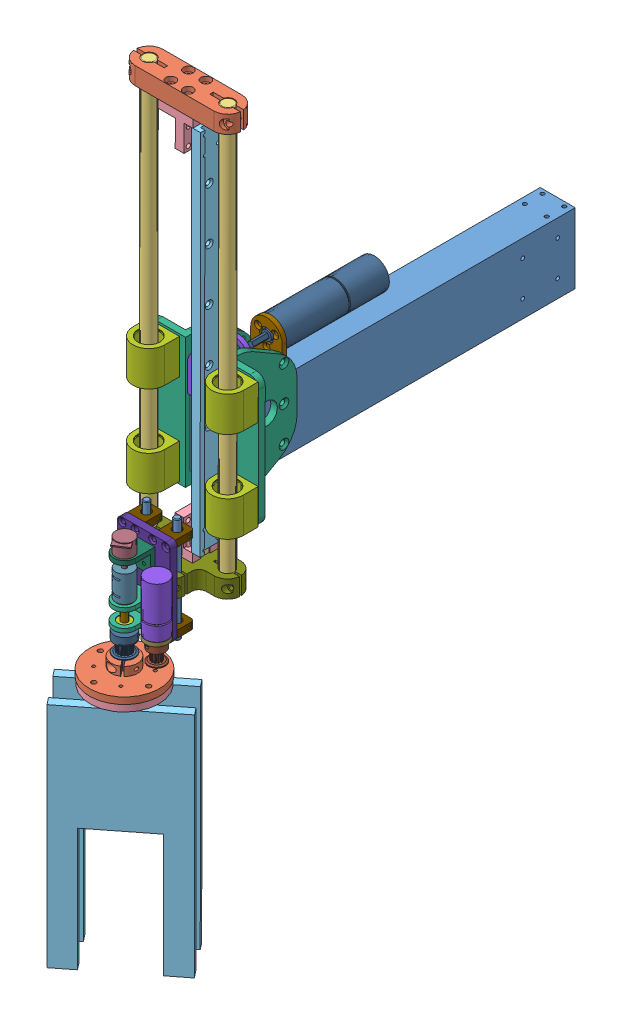
SolidWorks assembly wrist-certical-axis-ASM, configuration Default. Lengths in mm.
Overall size (90.81 526.28 357.5).
46 component instances, 29 part files, 16 mates.
Components (placement in the parent):
- a03-al-tube-1: a03-al-tube [Default] at origin size (25.4 50.8 254)
- wrist-vert-piece-1: wrist-vert-piece [Default] at (52.8069 226.0648 113.2865) x (1 0 0) z (0 0.000973 1) size (90.81 526.18 99.39)
  - w01-shaft-hold-tio-1: w01-shaft-hold-tio [Default] at (-52.8069 -5.7767 27.476) size (77.36 12.7 20.32)
  - xx-p5sHAFT-6253k32-mcm-1: xx-p5sHAFT-6253k32-mcm [Default] at (-81.3819 -145.4767 27.476) size (9.53 304.8 9.53)
  - xx-p5sHAFT-6253k32-mcm-3: xx-p5sHAFT-6253k32-mcm [Default] at (-24.2319 -145.4767 27.476) x (0 0 -1) z (1 0 0) size (9.53 304.8 9.53)
  - xx--fake-hand-asm-1: xx--fake-hand-asm [Default] at (-52.8069 -429.0793 73.5135) x (0.786463 0 -0.617638) z (-0.617638 0 -0.786463) size (76.2 175.18 50)
    - wrist-1: wrist [Default] at origin size (50 85 50)
    - xx-fake-hand-1: xx-fake-hand [Default] at (0 1.28 15.85) x (1 0 0) z (0 0 -1) size (76.2 165.1 6.35)
    - xx-fake-hand-2: xx-fake-hand [Default] at (0 1.28 -9.5) x (1 0 0) z (0 0 -1) size (76.2 165.1 6.35)
  - wrist-yaw-joint-1: wrist-yaw-joint [Default] at (-52.8069 -303.5917 59.5435) x (1 0 0) z (0 -1 0) size (76.14 66.56 87.16)
    - n05-headyoke-1: n05-headyoke [Default] at origin size (15.88 21.91 15.88)
    - p1875bearing-57155K319-MCM-1: p1875bearing-57155K319-MCM [Default] at (0 13.97 5.5499) x (0 0 -1) z (0 -1 0) size (3.17 11.18 11.18)
    - p1875bearing-57155K319-MCM-2: p1875bearing-57155K319-MCM [Default] at (0 13.97 -5.5499) x (0 0 1) z (0 -1 0) size (3.17 11.18 11.18)
    - MAXON-AMAX16-110049-110323-1: MAXON-AMAX16-110049-110323 [Default] at (17.4625 8.128 -28.5125) x (0 0 -1) z (1 0 0) size (48.2 16 16)
    - n06-p1875shaft-1: n06-p1875shaft [Default] at (0 13.97 -15.0749) size (4.76 4.76 50.8)
    - a_6d16-016df2506-p1875bore-16teeth-1: a_6d16-016df2506-p1875bore-16teeth [Default] at (0 13.97 17.218) x (0.167713 -0.985836 0) z (0 0 -1) size (14.73 14.73 14.29)
    - a_6d16m012df6003-3mm-bored-to-4mm-1: a_6d16m012df6003-3mm-bored-to-4mm [Default] at (17.4625 8.128 17.2524) x (-0.948708 0.316155 0) z (0 0 -1) size (12.2 12.2 14.3)
    - a_6n16-015df1206-2: a_6n16-015df1206 [Default] at (-14.2838 6.954 15.9813) x (0.986257 0.164531 -0.015045) z (-0.021924 0.040076 -0.998956) size (14.1 14.1 11.13) (hidden)
    - n09-motor-holder-1: n09-motor-holder [Default] at (17.4625 8.128 7.9375) size (33.53 16.26 2.79)
    - POT-eti-sys-EUP125-1: POT-eti-sys-EUP125 [Default] at (0 13.97 -47.4345) x (0 0 -1) z (0.836462 -0.548026 0) size (30.58 15.39 13)
    - 000_helical-coupling-6208K53-MCM-1: 000_helical-coupling-6208K53-MCM [Default] at (0 13.97 -18.3769) size (12.7 12.7 19.05)
    - n10-potholder-1: n10-potholder [Default] at (0 0 -29.5148) size (15.88 21.91 15.88)
    - w04-shaft-hold-bottom-2: w04-shaft-hold-bottom [Default] at (0 -32.0675 -5.715) x (1 0 0) z (0 1 0) size (76.14 12.7 34.92)
    - w06-plate-1: w06-plate [Default] at (0 0 -12.7) x (1 0 0) z (0 -1 0) size (38.1 63.5 5.08)
    - w07-clamp-1: w07-clamp [Default] at (11.1125 -13.0175 -43.815) size (12.7 14.29 5.08)
    - w07-clamp-2: w07-clamp [Default] at (11.1125 -13.0175 13.335) size (12.7 14.29 5.08)
    - w07-clamp-3: w07-clamp [Default] at (-11.1125 -13.0175 -43.815) size (12.7 14.29 5.08)
    - w07-clamp-4: w07-clamp [Default] at (-11.1125 -13.0175 13.335) size (12.7 14.29 5.08)
    - w08-p1875shaft-1: w08-p1875shaft [Default] at (-11.1125 -13.0175 -51.435) size (4.76 4.76 76.2)
    - w08-p1875shaft-2: w08-p1875shaft [Default] at (11.1125 -13.0175 -51.435) size (4.76 4.76 76.2)
  - w05-hand-mount-1: w05-hand-mount [Default] at (-52.8069 -344.0793 73.5135) x (0.786463 0 -0.617638) z (0.617638 0 0.786463) size (50.8 12.7 50.8)
  - 000_gearrack_mcm-6295K12-1: 000_gearrack_mcm-6295K12 [Default] at (-40.8689 -151.8267 27.476) x (0 -1 0) z (0 0 -1) size (266.7 6.35 6.35)
  - w10-el-2-el-1: w10-el-2-el [Default] at (-40.1069 -5.7767 27.476) x (1 0 0) z (0 0 -1) size (25.4 25.4 19.05)
  - w10-el-2-el-2: w10-el-2-el [Default] at (-40.1069 -285.1767 27.476) size (25.4 25.4 19.05)
  - w09-al-el-1: w09-al-el [Default] at (-40.8689 -145.4767 37.001) x (0 0 1) z (-1 0 0) size (19.05 266.7 6.35)
- side-plate-wrist-aseem-1: side-plate-wrist-aseem [Default] at (12.7 12.6846 98.425) x (0 -0.000973 -1) z (1 0 0) size (73.03 94.27 27.62)
  - w02-sideplate-1: w02-sideplate [Default] at origin size (50.8 94.27 27.62)
  - w03-bearing-holder-1: w03-bearing-holder [Default] at (-42.545 32.8463 15.875) size (22.23 25.4 22.86)
  - w03-bearing-holder-2: w03-bearing-holder [Default] at (-42.545 -32.8463 15.875) size (22.23 25.4 22.86)
- side-plate-wrist-aseem-2: side-plate-wrist-aseem [Default] at (-12.7 12.6846 98.425) x (0 -0.000973 -1) z (-1 0 0) size (73.03 94.27 27.62)
  - w02-sideplate-1: w02-sideplate [Default] at origin size (50.8 94.27 27.62)
  - w03-bearing-holder-1: w03-bearing-holder [Default] at (-42.545 32.8463 15.875) size (22.23 25.4 22.86)
  - w03-bearing-holder-2: w03-bearing-holder [Default] at (-42.545 -32.8463 15.875) size (22.23 25.4 22.86)
- w11-pinion-yoke-1: w11-pinion-yoke [Default] at (0 44.45 117.475) size (22.86 30.48 25.4)
- w12-motor-mount-pinion-1: w12-motor-mount-pinion [Default] at (0 44.45 81.026) size (22.86 30.48 22.23)
- MAXON-amax22-n-gear143991-1: MAXON-amax22-n-gear143991 [Default] at (0 44.45 35.226) x (0 0 -1) z (0.5 -0.866025 0) size (89.5 22 22)
Mates (geometry in assembly coordinates):
- Coincident1: coincident anti-aligned: plane of a03-al-tube-1 through (12.7 25.4 127) normal (1 0 0); plane of side-plate-wrist-aseem-1/w02-sideplate-1 through (12.7 -9.0246 123.8461) normal (-1 0 0)
- Coincident2: coincident anti-aligned: plane of a03-al-tube-1 through (-12.7 25.4 127) normal (-1 0 0); plane of side-plate-wrist-aseem-2/w02-sideplate-1 through (-12.7 34.4431 123.8039) normal (1 0 0)
- Concentric1: concentric anti-aligned: cylinder of side-plate-wrist-aseem-1/w02-sideplate-1; cylinder of side-plate-wrist-aseem-2/w02-sideplate-1
- Concentric2: concentric anti-aligned: cylinder of side-plate-wrist-aseem-1/w02-sideplate-1; cylinder of side-plate-wrist-aseem-2/w02-sideplate-1
- Concentric5: concentric anti-aligned: unknown of side-plate-wrist-aseem-2/w03-bearing-holder-2
- Concentric6: concentric aligned: unknown of side-plate-wrist-aseem-1/w03-bearing-holder-1
- Coincident3: coincident anti-aligned: plane of a03-al-tube-1 through (-12.7 25.4 127) normal (0 1 0); plane of w11-pinion-yoke-1 through (-11.43 25.4 130.175) normal (0 -1 0)
- Concentric7: concentric aligned: cylinder of a03-al-tube-1; cylinder of w11-pinion-yoke-1
- Concentric8: concentric aligned: cylinder of a03-al-tube-1; cylinder of w11-pinion-yoke-1
- Coincident4: coincident anti-aligned: plane of a03-al-tube-1 through (-12.7 25.4 127) normal (0 1 0); plane of w12-motor-mount-pinion-1 through (-11.43 25.4 84.201) normal (0 -1 0)
- Concentric11: concentric aligned: cylinder of w11-pinion-yoke-1; cylinder of w12-motor-mount-pinion-1
- Concentric12: concentric aligned: cylinder of w12-motor-mount-pinion-1; cylinder of MAXON-amax22-n-gear143991-1
- Coincident5: coincident aligned: plane of w12-motor-mount-pinion-1 through (0 44.45 81.026) normal (0 0 -1); circle of MAXON-amax22-n-gear143991-1 centre (0 44.45 81.026) axis (0 0 -1)
- Concentric13: concentric aligned: cylinder of w12-motor-mount-pinion-1; cylinder of MAXON-amax22-n-gear143991-1
- Distance1: distance = 1.524 mm anti-aligned: plane of w11-pinion-yoke-1 through (0 44.45 104.775) normal (0 0 -1); plane of w12-motor-mount-pinion-1 through (-11.43 28.575 103.251) normal (0 0 1)
- Concentric14: concentric aligned: cylinder of a03-al-tube-1; cylinder of side-plate-wrist-aseem-1/w02-sideplate-1
